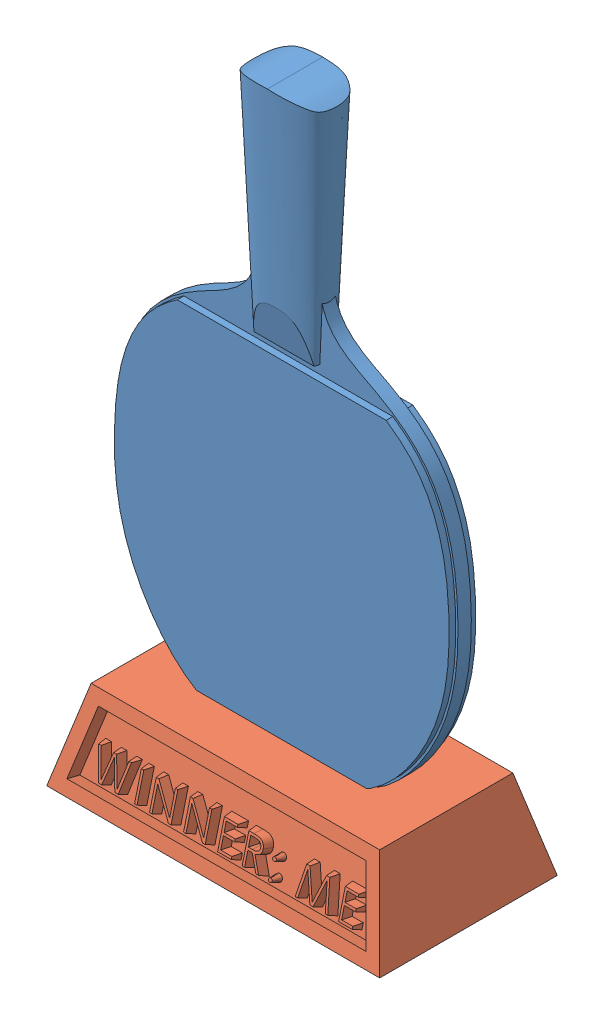
SolidWorks assembly Trophy10, configuration Default. Lengths in mm.
Overall size (154.7 298.35 80).
2 component instances, 2 part files, 0 mates.
Components (placement in the parent):
- Paddle10-1: Paddle10 [Default] at (-21.0589 112.3727 -14.5038) x (1 0 0) z (0 0 -1) size (154.7 269.43 27.53)
- Base-2: Base [Default] at (-20.9644 -21.7212 -17.5395) size (150 40 80)
